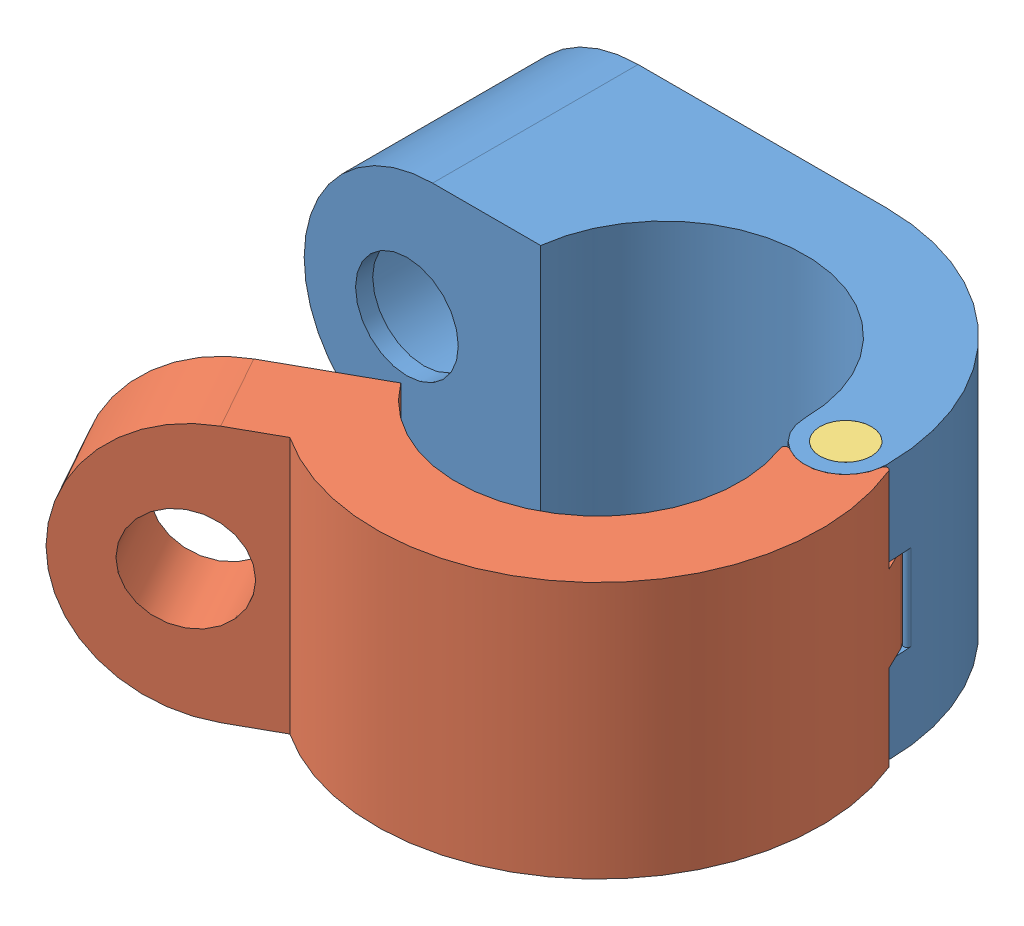
SolidWorks assembly Assemblage1, configuration Défaut. Lengths in mm.
Overall size (41.03 15 40.25).
3 component instances, 3 part files, 4 mates.
Components (placement in the parent):
- Canti partie 1 -1: Canti partie 1  [Défaut] at (42.7102 -16.7579 -7.4076) size (35 15 15.38)
- Canti partie 2 -1: Canti partie 2  [Défaut] at (44.0561 -16.7579 -2.2319) x (0.87333 0 -0.487129) z (0.487129 0 0.87333) size (35 15 15.38)
- axe 3mm-1: axe 3mm [Défaut] at (53.3352 -16.7579 -7.4076) size (3 15 3)
Mates (geometry in assembly coordinates):
- Coaxiale1: concentric aligned: cylinder of Canti partie 1 -1 through (53.3352 -16.7579 -7.4076) axis (0 1 0) radius 1.5; cylinder of Canti partie 2 -1 through (53.3352 -16.7579 -7.4076) axis (0 1 0) radius 1.5
- Coïncidente1: coincident anti-aligned: plane of Canti partie 1 -1 through (53.3352 -6.7579 -7.4076) normal (0 -1 0); plane of Canti partie 2 -1 through (53.3352 -6.7579 -7.4076) normal (0 1 0)
- Coaxiale2: concentric anti-aligned: cylinder of Canti partie 1 -1 through (53.3352 -16.7579 -7.4076) axis (0 1 0) radius 1.5; cylinder of axe 3mm-1 through (53.3352 -1.7579 -7.4076) axis (0 -1 0) radius 1.5
- Coïncidente2: coincident aligned: plane of Canti partie 1 -1 through (42.7102 -1.7579 -7.4076) normal (0 1 0); plane of axe 3mm-1 through (53.3352 -1.7579 -7.4076) normal (0 1 0)
